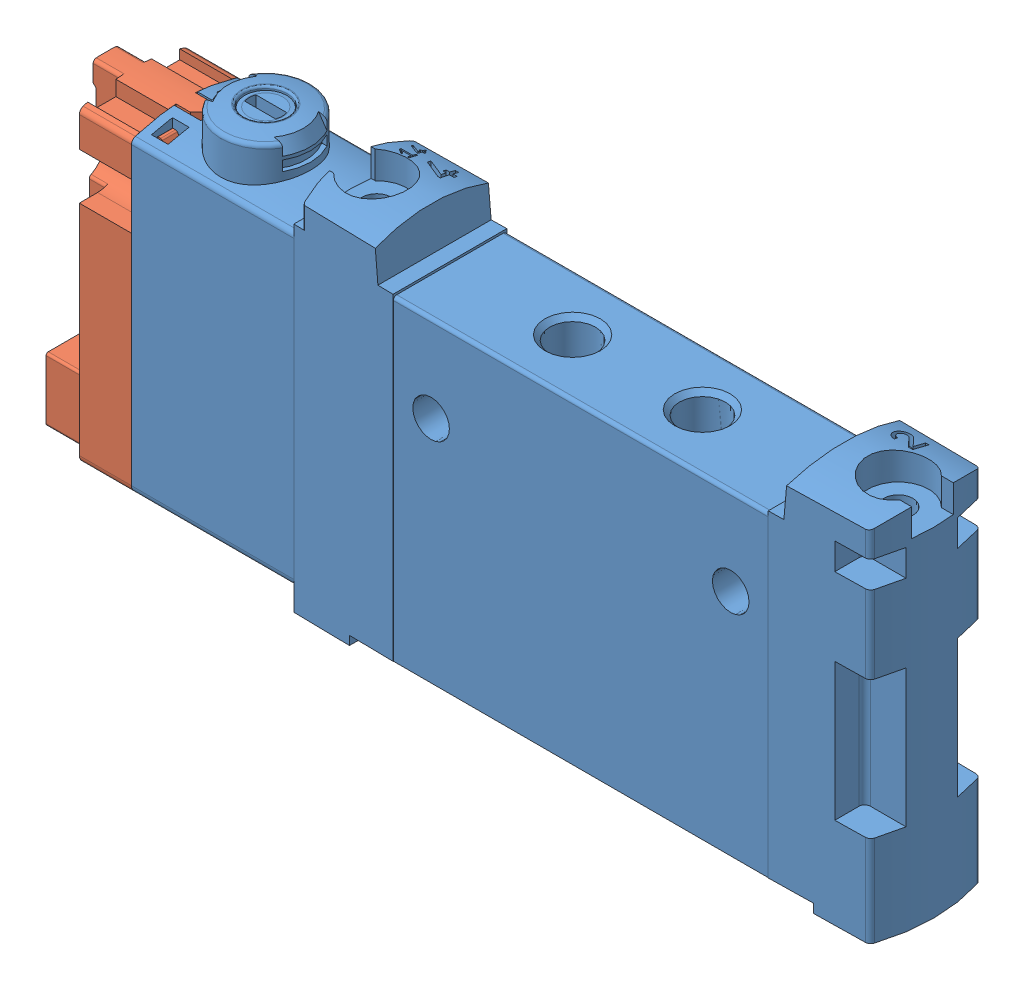
SolidWorks assembly 8042539_VUVG_LK10_M52_AT_M5_1H2L_S, configuration Default. Lengths in mm.
Overall size (75.85 33.47 10.25).
2 component instances, 2 part files, 3 mates.
Components (placement in the parent):
- 564212_VUVG_LK10_M52_A_T_M5__1H2__L______G_-1: 564212_VUVG_LK10_M52_A_T_M5__1H2__L______G_ [Default] at origin
- 3779382_VUVG_LK_IP40-1: 3779382_VUVG_LK_IP40 [Default] at (-40.7 1 0) x (-1 0 0) z (0 0 -1)
Mates (geometry in assembly coordinates):
- Distance1: distance = 0 mm: plane of 564212_VUVG_LK10_M52_A_T_M5__1H2__L______G_-1 through (0 1.2 0) normal (0 1 0); plane of 3779382_VUVG_LK_IP40-1
- Coincident1: coincident: line of 564212_VUVG_LK10_M52_A_T_M5__1H2__L______G_-1 through (-41.62 50 0) axis (0 -1 0); line of 3779382_VUVG_LK_IP40-1 through (-41.62 -49 0) axis (0 1 0)
- Angle3: planar angle = 3.141593 rad: plane of 3779382_VUVG_LK_IP40-1 through (-41.62 1 0) normal (-1 0 0); plane of 564212_VUVG_LK10_M52_A_T_M5__1H2__L______G_-1 through (-41.62 0 0) normal (1 0 0)
